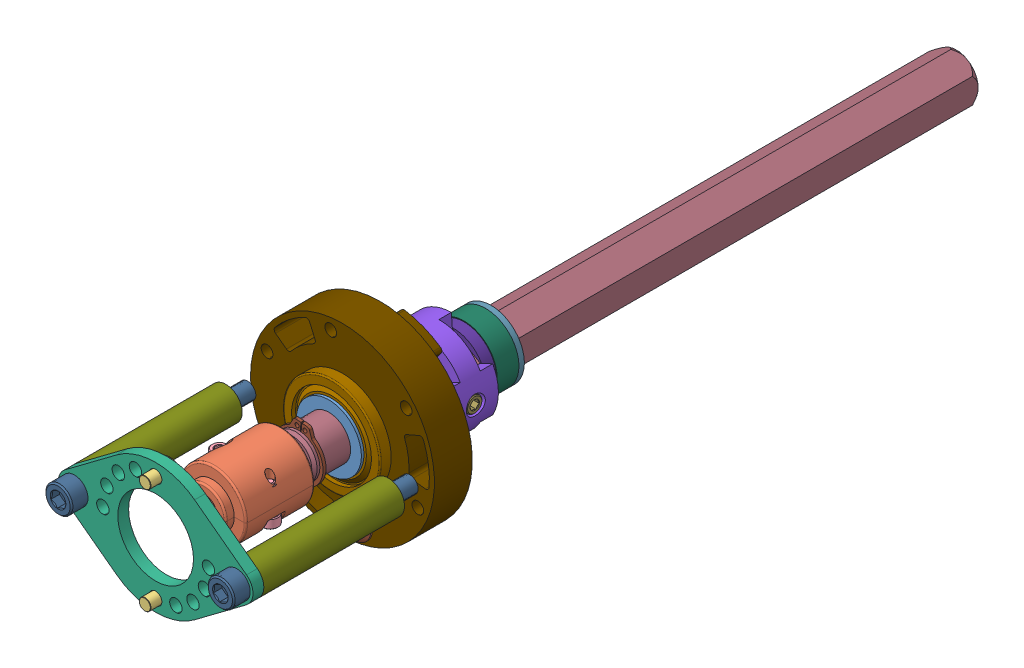
SolidWorks assembly 217-3636-KIT-STEP, configuration Default. Lengths in mm.
Overall size (61.19 61.19 240).
30 component instances, 21 part files, 0 mates.
Components (placement in the parent):
- 217-2428-027 Rev1_97414A630-1: 217-2428-027 Rev1_97414A630 [Default] at (0 45.7708 99.4031) x (0 0 1) z (-0.998671 -0.051538 0) size (0.64 5.89 7.9)
- 217-3195-200 Rev1-1: 217-3195-200 Rev1 [Default] at (0 45.7708 103.048) x (-1 0 0) z (0 0 1) size (20.44 19.56 22.71)
  - 217-3195-010 Rev1-1: 217-3195-010 Rev1 [Default] x (-1 0 0) z (0 0 1) size (19.61 11.78 22.71)
  - 217-3195-010 Rev1-2: 217-3195-010 Rev1 [Default] at origin size (19.61 11.78 22.71)
  - 217-2778-NCQ8A075-050M_1032_Nut_90545A111-1: 217-2778-NCQ8A075-050M_1032_Nut_90545A111 [Default] at (0 0 2.5527) x (-0.5 0.866025 0) z (0 0 1) size (9.53 11 3.39)
  - 91251A107_91251A107-1: 91251A107_91251A107 [Default] at (-7.4168 -4.9375 -0.635) x (1 0 0) z (0 -1 0) size (4.65 4.65 10.79)
  - 91251A107_91251A107-2: 91251A107_91251A107 [Default] at (7.4168 4.9375 -0.635) x (-0.837169 0 -0.546944) z (0 1 0) size (4.65 4.65 10.79)
- 217-3489-1: 217-3489 [Default] at (0 45.7708 96.6028) x (0 0 -1) z (-0.103791 0.994599 0) size (4.77 12.7 12.7)
- 217-3423-005 Rev1-1: 217-3423-005 Rev1 [Default] at (0 45.7708 127) size (57.15 38.1 3.17)
- 217-3423-008 Rev1-1: 217-3423-008 Rev1 [Default] at (0 45.7708 91.7323) x (0 -1 0) z (0 0 -1) size (7.14 7.14 57.15)
- 217-3423-009 Rev1-1: 217-3423-009 Rev1 [Default] at (0 45.7708 48.1269) x (-1 0 0) z (0 0 1) size (26.99 26.99 13.24)
- 217-2778-001 Rev2_NCQ8A075-050M-1: 217-2778-001 Rev2_NCQ8A075-050M [Default] at (0 45.7708 142.0495) x (1 0 0) z (0 0 -1) size (13.75 14.29 3.39)
  - 217-2778-NCQ8A075-050M_1032_Nut_90545A111-1: 217-2778-NCQ8A075-050M_1032_Nut_90545A111 [Default] at (0 0 39.827) x (0.866025 0.5 0) z (0 0 1) size (9.53 11 3.39)
- 217-2743-1: 217-2743 [Default] at (0 45.7708 73.025) x (0 0 -1) z (0.939414 -0.342784 0) size (7.94 28.57 28.57)
- 217-3421-007 Rev1-1: 217-3421-007 Rev1 [Default] at (23.8125 45.7708 128.5875) x (0 0 -1) z (0.991978 -0.126413 0) size (55.85 7.92 7.92)
- 217-3421-007 Rev1-2: 217-3421-007 Rev1 [Default] at (-23.8125 45.7708 128.5875) x (0 0 -1) z (0.991978 -0.126413 0) size (55.85 7.92 7.92)
- 217-3421-011 Rev2_97633A200-1: 217-3421-011 Rev2_97633A200 [Default] at (0 45.7708 86.1695) x (0 0 1) z (-0.99554 0.094343 0) size (0.89 16.1 14.34)
- 217-3423-014 Rev1-1: 217-3423-014 Rev1 [Default] at (-13.4938 45.7708 48.1269) x (0 -0.673339 -0.739334) z (-1 0 0) size (4.65 4.65 26.79)
- 217-3423-003 Rev1-1: 217-3423-003 Rev1 [Default] at (0 45.7708 55.1656) x (0 1 0) z (0 0 -1) size (18.33 15.88 194.69)
- 217-3257-001 Rev1-1: 217-3257-001 Rev1 [Default] at (0 45.7708 30.9563) size (19.5 19.5 1.59)
- 217-3259-001 Rev1-1: 217-3259-001 Rev1 [Default] at (0 45.7708 34.925) x (0.995688 -0.092763 0) z (0 0 1) size (19.5 19.5 6.35)
- 217-3423-006 Rev1-1: 217-3423-006 Rev1 [Default] at (-23.8125 45.7708 104.775) x (0 0 1) z (-1 0 0) size (41.27 9.53 9.53)
- 217-3423-006 Rev1-2: 217-3423-006 Rev1 [Default] at (23.8125 45.7708 104.775) x (0 0 1) z (-1 0 0) size (41.27 9.53 9.53)
- 217-2758-001 Rev1-1: 217-2758-001 Rev1 [Default] at (0 45.7708 39.6875) x (0.999998 -0.001993 0) z (0 0 1) size (19.05 19.05 3.17)
- 217-3433-002 Rev1-1: 217-3433-002 Rev1 [Default] at (0 45.7708 69.0087) x (0.144045 -0.989571 0) z (0 0 -1) size (53.98 53.98 14.29)
- 217-3423-004 Rev1-1: 217-3423-004 Rev1 [Default] at (0 45.7708 77.3748) size (19.05 19.05 0.76)
- 217-3423-016 Rev1-1: 217-3423-016 Rev1 [Default] at (-16.1541 36.4442 85.725) x (0 0 -1) z (1 0 0) size (11.03 9.26 9.25)
- 217-3423-016 Rev1-2: 217-3423-016 Rev1 [Default] at (16.1541 36.4442 85.725) x (0 0 -1) z (1 0 0) size (11.03 9.26 9.25)
- SBS1_SBS-0632-0250-1: SBS1_SBS-0632-0250 [Default] at (0 30.2768 123.5583) x (0 0 1) z (-0.996907 -0.078591 0) size (8.57 6.68 6.65)
- SBS1_SBS-0632-0250-2: SBS1_SBS-0632-0250 [Default] at (0 61.2648 123.5583) x (0 0 1) z (0.996907 0.078591 0) size (8.57 6.68 6.65)
